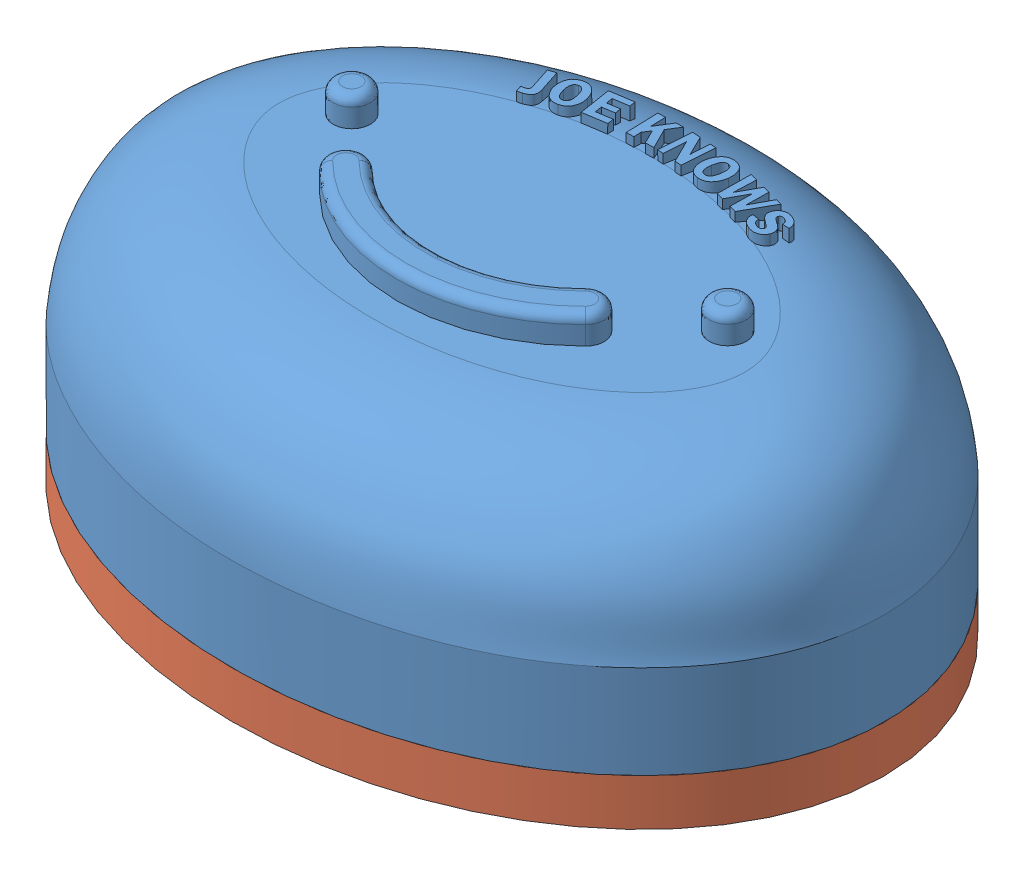
SolidWorks assembly SensorEnclosureAssembly, configuration Default. Lengths in mm.
Overall size (80.25 33 60.21).
2 component instances, 2 part files, 3 mates.
Components (placement in the parent):
- SensorEnclosure-1: SensorEnclosure [Default] at origin size (80.25 28 60.21)
- SensorEnclosureLid-1: SensorEnclosureLid [Default] at (0 -5 0) size (80 8 60)
Mates (geometry in assembly coordinates):
- Distance4: distance = 0 mm: plane of SensorEnclosure-1 through (0 0 0) normal (0 -1 0); plane of SensorEnclosureLid-1 through (0 0 0) normal (0 1 0)
- Distance2: distance = 1 mm: plane of SensorEnclosureLid-1 through (19 3 -19) normal (0 0 -1); plane of SensorEnclosure-1 through (-20 10 -20) normal (0 0 1)
- Distance3: distance = 1 mm: plane of SensorEnclosureLid-1 through (26.5 3 16.5) normal (1 0 0); plane of SensorEnclosure-1 through (27.5 19 -17.5) normal (-1 0 0)
